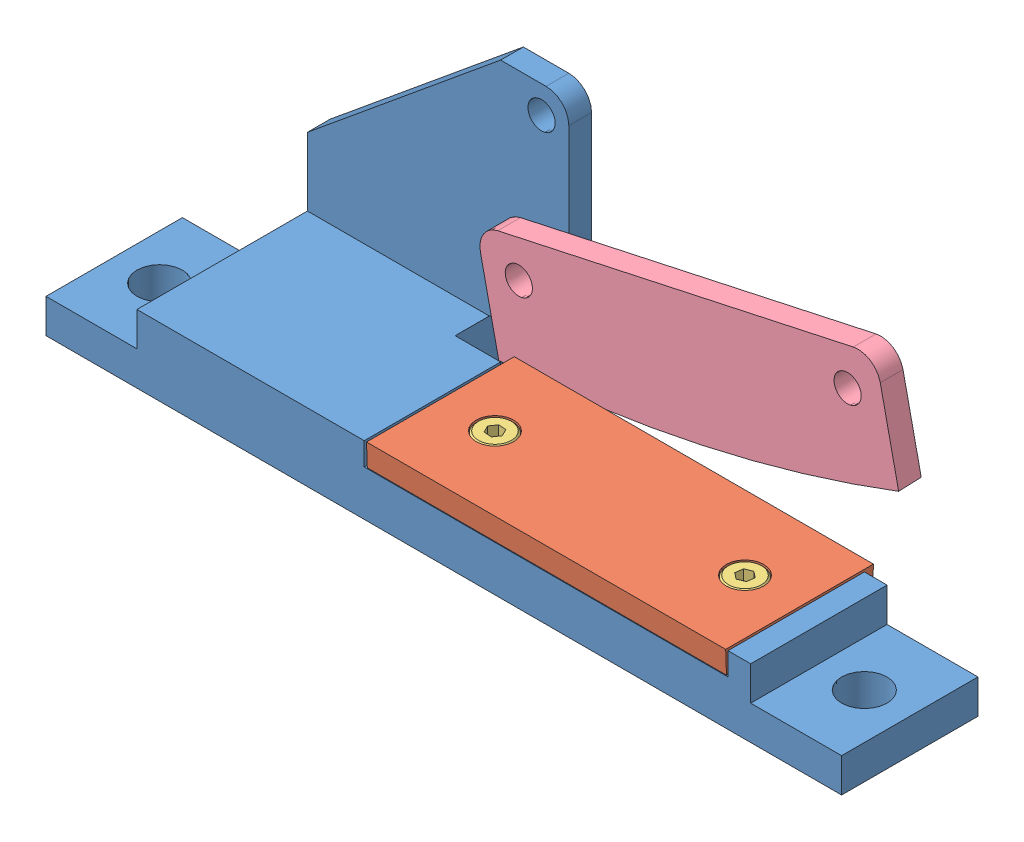
SolidWorks assembly Assem4, configuration Default. Lengths in mm.
Overall size (350 130 85).
5 component instances, 4 part files, 9 mates.
Components (placement in the parent):
- Base-1: Base [Default] at (127.495 129.1058 275.034) size (350 130 85)
- Lower blade-1: Lower blade [Default] at (172.495 149.1058 272.534) size (158 10 65)
- M10 allen bolt-1: M10 allen bolt [Default] at (117.495 154.1058 272.534) x (0.435197 0 0.900335) z (0 -1 0) size (16 16 20)
- M10 allen bolt-2: M10 allen bolt [Default] at (227.495 154.1058 272.534) x (0.127842 0 -0.991795) z (0 -1 0) size (16 16 20)
- Upper blade-1: Upper blade [Default] at (176.0753 166.6603 235.034) x (0.977322 0.211757 0) z (0 0 1) size (180 55 10)
Mates (geometry in assembly coordinates):
- Coincident3: coincident: plane of Base-1 through (127.495 149.1058 275.034) normal (0 1 0); plane of Lower blade-1 through (172.495 149.1058 272.534) normal (0 -1 0)
- Concentric6: concentric: cylinder of Base-1 through (95.495 189.1058 220.033) axis (0 0 1) radius 6; cylinder of Upper blade-1 through (95.495 189.1058 240.034) axis (0 0 -1) radius 6
- Coincident12: coincident: plane of Base-1 through (127.495 129.1058 230.034) normal (0 0 1); plane of Upper blade-1 through (49.0209 753.0536 230.034) normal (0 0 -1)
- Concentric7: concentric: cylinder of Base-1 through (117.495 149.1058 272.534) axis (0 1 0) radius 4.25; circle of Lower blade-1
- Concentric8: concentric: cylinder of Base-1 through (227.495 149.1058 272.534) axis (0 1 0) radius 4.25; cylinder of Lower blade-1 through (227.495 149.1058 272.534) axis (0 1 0) radius 5
- Concentric10: concentric: cylinder of Base-1 through (117.495 149.1058 272.534) axis (0 1 0) radius 4.25; cylinder of M10 allen bolt-1 through (117.495 139.1058 272.534) axis (0 1 0) radius 5
- Coincident13: coincident: plane of Lower blade-1 through (117.495 154.1058 272.534) normal (0 1 0); plane of M10 allen bolt-1 through (117.495 154.1058 272.534) normal (0 -1 0)
- Concentric11: concentric: cylinder of Base-1 through (227.495 149.1058 272.534) axis (0 1 0) radius 4.25; cylinder of M10 allen bolt-2 through (227.9855 159.1058 265.5547) axis (0 1 0) radius 5
- Coincident14: coincident: plane of Lower blade-1 through (227.495 154.1058 272.534) normal (0 1 0); plane of M10 allen bolt-2 through (227.495 154.1058 272.534) normal (0 -1 0)
